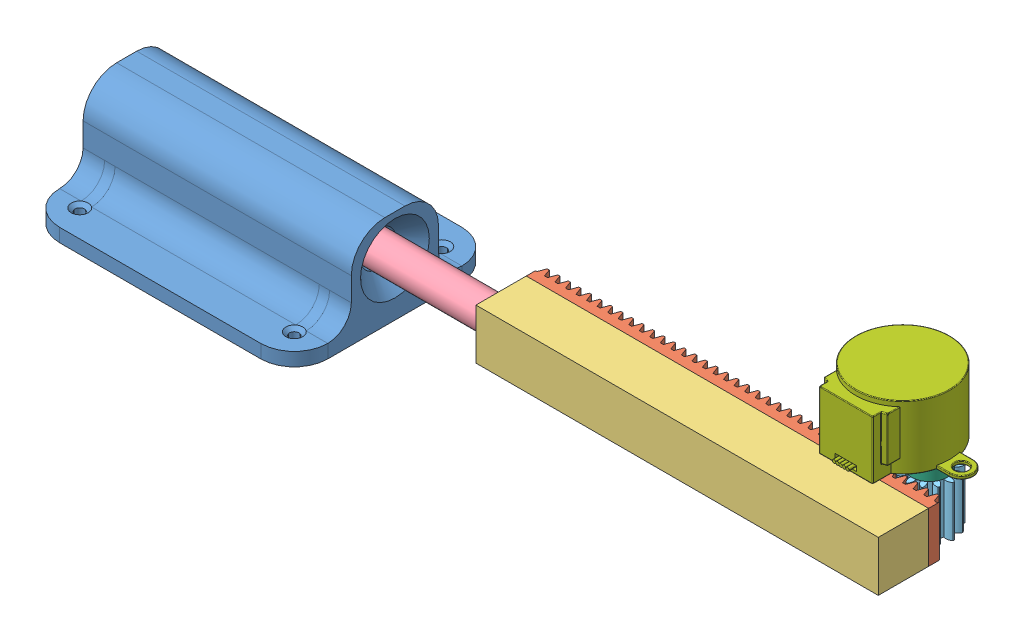
SolidWorks assembly full_lock_assembly_animatino, configuration Default. Lengths in mm.
Overall size (242.19 54.5 107.94).
9 component instances, 7 part files, 7 mates.
Components (placement in the parent):
- lock plate-1: lock plate [Default] at origin size (80 28 60)
- rackblock assembly-1: rackblock assembly [Default] at (131.6662 16 7.5) x (1 0 0) z (0 1 0) size (230 20 15)
  - rack spur rectangular_am-1: rack spur rectangular_am [Metric - Rack-spur - rectangular 1M 20PA 15mmFW 4PH 120L---SAll] at (-60 15 7.5) size (120 5 15)
  - rackblock-1: rackblock [Default] at origin size (120 15 15)
  - barrel-2: barrel [Default] at (-170 7.5 0) x (1 0 0) z (0 -0.983109 0.183021) size (220 9.53 9.53)
- motor_pinion assembly-1: motor_pinion assembly [Default] at (181.1905 31.5 -18.2383) x (-1 0 0) z (0 0 1) size (117.54 46 86.18) (flexible)
  - spur gear_am-1: spur gear_am [Metric - Spur gear 1M 13T 20PA 15FW ---S13N75H50L3N] at (0 8 0) x (0 1 0) z (-0.497437 0 -0.8675) size (15 114.5 14.93)
  - pinion block-1: pinion block [Default] at origin size (10.5 23 10.5)
  - Stepper_28BYJ-48-2: Stepper_28BYJ-48 [Default] at (0 -23 7.975) x (0 0 1) z (-1 0 0) size (32.5 29 42)
Mates (geometry in assembly coordinates):
- Coincident8: coordinate: point of lock plate-1
- Concentric5: concentric anti-aligned: cylinder of lock plate-1 through (-40 16 0) axis (1 0 0) radius 5.2625; cylinder of rackblock assembly-1/barrel-2 through (181.6662 16 0) axis (-1 0 0) radius 4.7625
- Parallel3: parallel aligned: plane of lock plate-1 through (-40 4 30) normal (0 0 1); plane of rackblock assembly-1/rackblock-1 through (131.6662 16 7.5) normal (0 0 1)
- Parallel6: parallel aligned: plane of lock plate-1 through (0 0 0) normal (0 -1 0); plane of motor_pinion assembly-1/Stepper_28BYJ-48-2 through (181.1905 35.5 -10.2633) normal (0 -1 0)
- Parallel4: parallel aligned: plane of lock plate-1 through (-40 4 30) normal (0 0 1); plane of motor_pinion assembly-1/Stepper_28BYJ-48-2 through (173.1905 35.5 6.7367) normal (0 0 1)
- Coincident13: coincident aligned: plane of rackblock assembly-1/rack spur rectangular_am-1 through (71.6662 8.5 -12.5) normal (0 -1 0); plane of motor_pinion assembly-1/spur gear_am-1 through (181.1905 8.5 -18.2383) normal (0 -1 0)
- RackPinionMate3: rack pinion = 13 mm: line of rackblock assembly-1/rackblock-1 through (191.6662 8.5 -7.5) axis (-1 0 0); circle of motor_pinion assembly-1/spur gear_am-1
